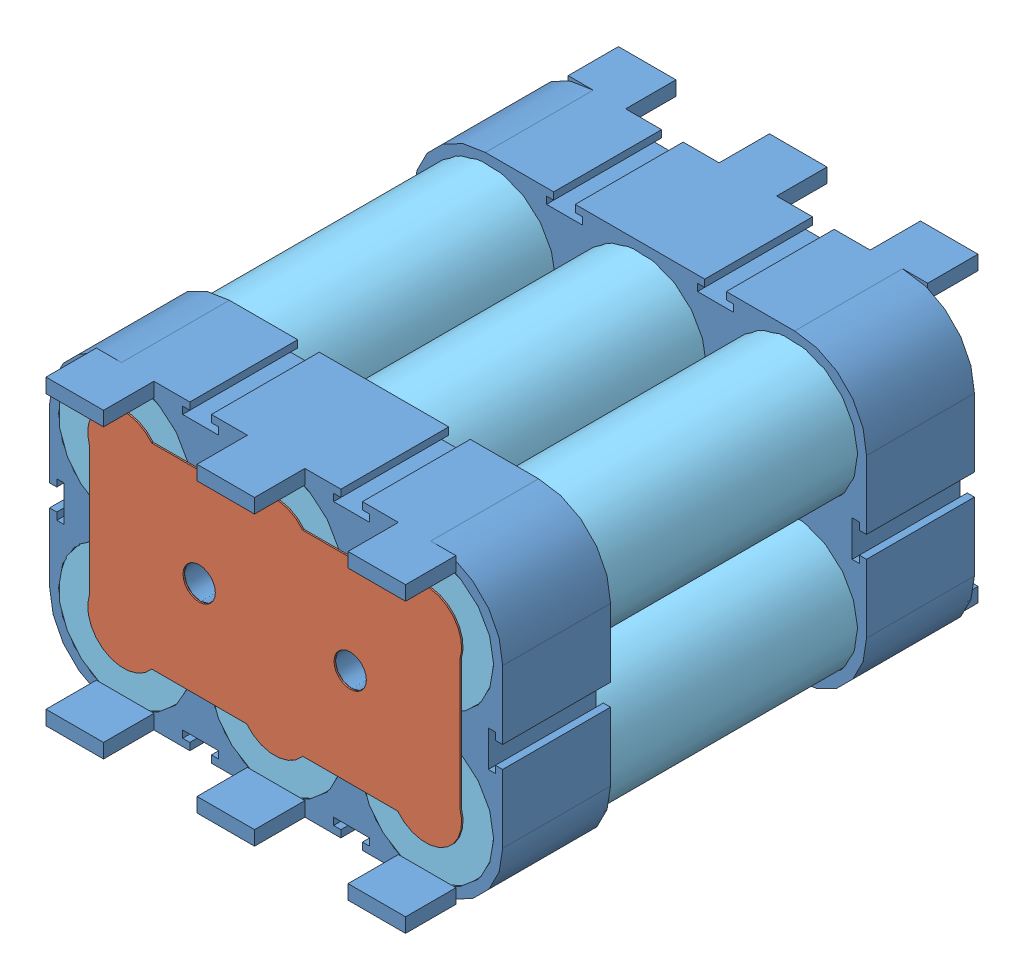
SolidWorks assembly 6P_Cell_Pack, configuration Default. Lengths in mm.
Overall size (70.31 49.31 71.6).
28 component instances, 5 part files, 12 mates.
Components (placement in the parent):
- Cell_Holder_6P-1: Cell_Holder_6P [Default] at origin size (63 42 18)
- Cell_Holder_6P-2: Cell_Holder_6P [Default] at (63 0 -35.6) x (-1 0 0) z (0 0 -1) size (63 42 18)
- Contact_Plate-1: Contact_Plate [Default] at (5.5 5.515 15) x (1 0 0) z (0 -1 0) size (52 0.2 30.97)
- Contact_Plate-2: Contact_Plate [Default] at (5.5 5.515 -50.8) x (1 0 0) z (0 -1 0) size (52 0.2 30.97)
- 18650_wrapped-1: 18650_wrapped [Default] at (10.5 31.5 14.75) x (0.990631 -0.136562 0) z (0.136562 0.990631 0) size (25.12 65.6 25.12)
  - 18650-1: 18650 [Default] at origin size (18 65 18)
  - Insulator_donut-1: Insulator_donut [Default] at (0 64.8 0) x (0.970599 0 -0.240704) z (0.240704 0 0.970599) size (18 0.3 18)
  - 18650_Shrinkwarp-1: 18650_Shrinkwarp [Default] x (0.480873 0 0.87679) z (-0.87679 0 0.480873) size (18.5 65.6 18.5)
- 18650_wrapped-2: 18650_wrapped [Default] at (31.5 31.5 14.75) x (0.990631 -0.136562 0) z (0.136562 0.990631 0) size (25.12 65.6 25.12)
  - 18650-1: 18650 [Default] at origin size (18 65 18)
  - Insulator_donut-1: Insulator_donut [Default] at (0 64.8 0) x (0.970599 0 -0.240704) z (0.240704 0 0.970599) size (18 0.3 18)
  - 18650_Shrinkwarp-1: 18650_Shrinkwarp [Default] x (0.480873 0 0.87679) z (-0.87679 0 0.480873) size (18.5 65.6 18.5)
- 18650_wrapped-3: 18650_wrapped [Default] at (52.5 31.5 14.75) x (0.990631 -0.136562 0) z (0.136562 0.990631 0) size (25.12 65.6 25.12)
  - 18650-1: 18650 [Default] at origin size (18 65 18)
  - Insulator_donut-1: Insulator_donut [Default] at (0 64.8 0) x (0.970599 0 -0.240704) z (0.240704 0 0.970599) size (18 0.3 18)
  - 18650_Shrinkwarp-1: 18650_Shrinkwarp [Default] x (0.480873 0 0.87679) z (-0.87679 0 0.480873) size (18.5 65.6 18.5)
- 18650_wrapped-4: 18650_wrapped [Default] at (10.5 10.5 14.75) x (0.990631 -0.136562 0) z (0.136562 0.990631 0) size (25.12 65.6 25.12)
  - 18650-1: 18650 [Default] at origin size (18 65 18)
  - Insulator_donut-1: Insulator_donut [Default] at (0 64.8 0) x (0.970599 0 -0.240704) z (0.240704 0 0.970599) size (18 0.3 18)
  - 18650_Shrinkwarp-1: 18650_Shrinkwarp [Default] x (0.480873 0 0.87679) z (-0.87679 0 0.480873) size (18.5 65.6 18.5)
- 18650_wrapped-5: 18650_wrapped [Default] at (31.5 10.5 14.75) x (0.990631 -0.136562 0) z (0.136562 0.990631 0) size (25.12 65.6 25.12)
  - 18650-1: 18650 [Default] at origin size (18 65 18)
  - Insulator_donut-1: Insulator_donut [Default] at (0 64.8 0) x (0.970599 0 -0.240704) z (0.240704 0 0.970599) size (18 0.3 18)
  - 18650_Shrinkwarp-1: 18650_Shrinkwarp [Default] x (0.480873 0 0.87679) z (-0.87679 0 0.480873) size (18.5 65.6 18.5)
- 18650_wrapped-6: 18650_wrapped [Default] at (52.5 10.5 14.75) x (0.990631 -0.136562 0) z (0.136562 0.990631 0) size (25.12 65.6 25.12)
  - 18650-1: 18650 [Default] at origin size (18 65 18)
  - Insulator_donut-1: Insulator_donut [Default] at (0 64.8 0) x (0.970599 0 -0.240704) z (0.240704 0 0.970599) size (18 0.3 18)
  - 18650_Shrinkwarp-1: 18650_Shrinkwarp [Default] x (0.480873 0 0.87679) z (-0.87679 0 0.480873) size (18.5 65.6 18.5)
Mates (geometry in assembly coordinates):
- Coincident3: coincident: plane of assembly; plane of assembly; plane of Cell_Holder_6P-1 through (0 42 15) normal (0 1 0); plane of Cell_Holder_6P-2 through (63 42 -50.6) normal (0 1 0)
- Coincident11: coincident: circle of assembly; cylinder of assembly; circle of Cell_Holder_6P-1; cylinder of Contact_Plate-1 through (42 21 15.2) axis (0 0 -1) radius 2.25
- Coincident12: coincident: plane of assembly; plane of assembly; plane of Cell_Holder_6P-1 through (0 0 15) normal (0 0 1); plane of Contact_Plate-1 through (5.5 5.515 15) normal (0 0 -1)
- Concentric10: concentric: circle of assembly; circle of assembly; circle of Cell_Holder_6P-2; circle of Contact_Plate-2
- Coincident13: coincident: plane of assembly; plane of assembly; plane of Cell_Holder_6P-2 through (63 0 -50.6) normal (0 0 -1); plane of Contact_Plate-2 through (5.5 5.515 -50.6) normal (0 0 1)
- Concentric11: concentric: circle of assembly; circle of assembly; circle of Cell_Holder_6P-2; circle of Contact_Plate-2
- Concentric12: concentric: circle of assembly; circle of assembly; circle of Cell_Holder_6P-1; circle of Contact_Plate-1
- Concentric13: concentric: cylinder of assembly; cylinder of assembly; cylinder of Cell_Holder_6P-1 through (10.5 31.5 15) axis (0 0 -1) radius 9.25; cylinder of 18650_wrapped-1/18650_Shrinkwarp-1 through (10.5 31.5 -50.35) axis (0 0 1) radius 9.25
- Coincident16: coincident: plane of assembly; plane of assembly; plane of Cell_Holder_6P-1 through (0 0 15) normal (0 0 -1); plane of 18650_wrapped-1/18650_Shrinkwarp-1 through (10.5 31.5 15) normal (0 0 1)
- Concentric14: concentric: cylinder of assembly; cylinder of assembly; cylinder of Cell_Holder_6P-2 through (10.5 31.5 -50.6) axis (0 0 1) radius 9.25; cylinder of 18650_wrapped-1/18650_Shrinkwarp-1 through (10.5 31.5 -50.35) axis (0 0 1) radius 9.25
- Coincident17: coincident: plane of assembly; plane of assembly; plane of Cell_Holder_6P-2 through (63 0 -50.6) normal (0 0 1); plane of 18650_wrapped-1/18650_Shrinkwarp-1 through (10.5 31.5 -50.6) normal (0 0 -1)
- Coincident18: coincident: plane of assembly; plane of assembly; plane of Cell_Holder_6P-1 through (0 0 15) normal (-1 0 0); plane of Cell_Holder_6P-2 through (0 0 -50.6) normal (-1 0 0)
